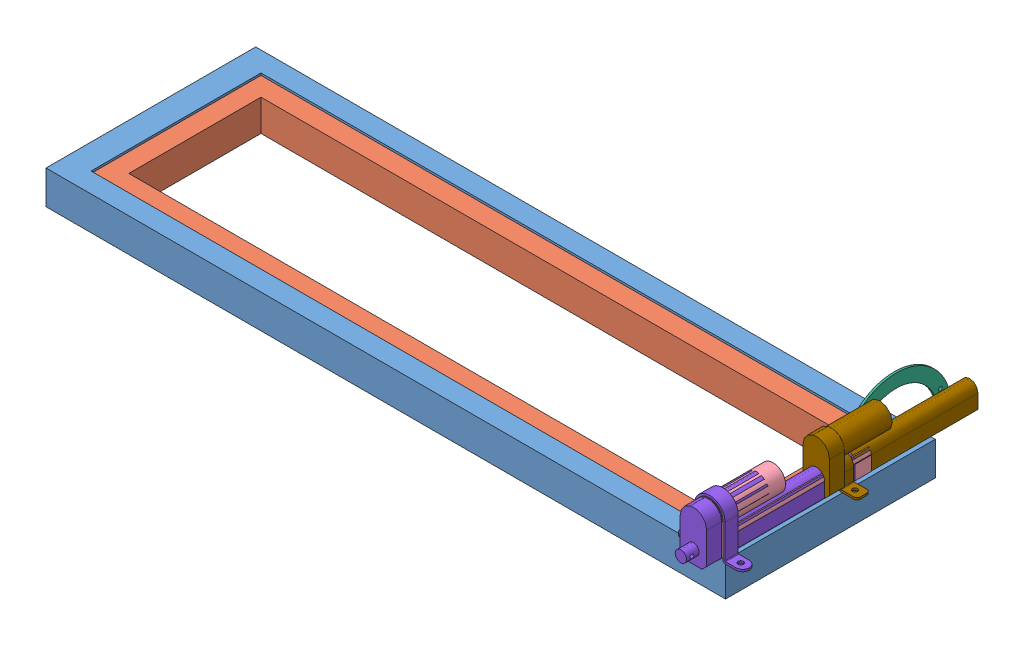
SolidWorks assembly Ensamblaje3, configuration Predeterminado. Lengths in mm.
Overall size (1059.65 147.79 411.91).
12 component instances, 9 part files, 23 mates.
Components (placement in the parent):
- Marco-1: Marco [Predeterminado] at (-53.8261 1.3636 0) size (1028.7 50.8 317.5)
- Ventana-1: Ventana [Predeterminado] at (-53.8261 1.3636 0) x (-1 0 0) z (0 0 -1) size (976.25 47.62 280.92)
- Bisabra-1: Bisabra [Default] at (97.2328 -11.1577 -174.3841) x (0 1 0) z (1 0 0) size (54 16 72) (flexible)
  - Bisagra-1: Bisagra [Default] at (4.5212 31.9216 19.0662) size (54 16 36)
  - Bisagra-2: Bisagra [Default] at (4.5212 31.9216 91.0662) x (1 0 0) z (0 0 -1) size (54 16 36)
- Motor150-1: Motor150 [Default] at (344.8659 -52.5107 -126.6133) size (40.01 75 401.08) (flexible)
  - motor150-1: motor150 [Predeterminado] at (96.608 131.4242 267.3633) x (1 0 0) z (0 -1 0) size (40.01 251 75)
  - eje150-1: eje150 [Predeterminado] at (96.608 124.1742 -70.716) x (-1 0 0) z (0 1 0) size (20 171 20)
- SoporteAperturaOpcion3-1: SoporteAperturaOpcion3 [Default] at (417.4739 75.5831 -75.6768) x (0 -0.100235 -0.994964) z (1 0 0) size (158.53 73.48 17.18)
- soportemotor18-2: soportemotor18 [Default] at (420.6489 78.9886 -85.0125) x (-1 0 0) z (0 0 1) size (25 30 20)
- SujetadorMotor-1: SujetadorMotor [Default] at (440.1188 79.4136 143.75) x (1 0 0) z (0 -1 0) size (103.17 251 78.17)
- SujetadorMotorDelantero-1: SujetadorMotorDelantero [Default] at (461.9608 78.2879 -38.25) x (1 0 0) z (0 -1 0) size (60.97 251 75)
Mates (geometry in assembly coordinates):
- Width1: width anti-aligned: plane of Marco-1 through (-545.9511 48.9886 0) normal (1 0 0); plane of Ventana-1 through (438.2989 48.9886 0) normal (-1 0 0); plane of Marco-1 through (-541.9511 48.9886 0) normal (-1 0 0); plane of Ventana-1 through (434.2989 48.9886 0) normal (1 0 0)
- Coincident2: coincident anti-aligned: plane of Marco-1 through (-53.8261 48.9886 -144.4625) normal (0 0 1); plane of Bisabra-1/Bisagra-2 through (152.2989 39.3636 -144.4625) normal (0 0 -1)
- Coincident3: coincident anti-aligned: plane of Marco-1 through (-53.8261 1.3636 0) normal (0 -1 0); plane of Bisabra-1/Bisagra-2 through (152.2989 1.3636 -144.4625) normal (0 1 0)
- Coincident4: coincident anti-aligned: plane of Ventana-1 through (-53.8261 48.9886 -140.4625) normal (0 0 -1); plane of Bisabra-1/Bisagra-1 through (152.2989 39.3636 -140.4625) normal (0 0 1)
- Coincident5: coincident anti-aligned: plane of Ventana-1 through (-53.8261 1.3636 0) normal (0 -1 0); plane of Bisabra-1/Bisagra-1 through (152.2989 1.3636 -140.4625) normal (0 1 0)
- Distance1: distance = 250 mm anti-aligned: plane of Marco-1 through (438.2989 48.9886 0) normal (-1 0 0); plane of Bisabra-1/Bisagra-2 through (188.2989 37.3636 -144.4625) normal (1 0 0)
- Concentric11: concentric anti-aligned: cylinder of Motor150-1/eje150-1 through (453.9739 71.6636 -209.3292) axis (-1 0 0) radius 3; cylinder of SoporteAperturaOpcion3-1 through (414.2989 71.6636 -209.3292) axis (1 0 0) radius 3
- Tangent1: tangent anti-aligned: cylinder of Motor150-1/eje150-1 through (441.4739 71.6636 -218.3292) axis (0 0 1) radius 10; plane of SoporteAperturaOpcion3-1 through (431.4739 75.5831 -75.6768) normal (1 0 0)
- Parallel7: parallel anti-aligned: plane of Marco-1 through (-53.8261 52.1636 0) normal (0 1 0); plane of Motor150-1/motor150-1 through (441.4739 52.1636 -68.25) normal (0 -1 0)
- Coincident43: coincident anti-aligned: plane of Ventana-1 through (-53.8261 48.9886 0) normal (0 1 0); plane of soportemotor18-2 through (420.6489 48.9886 -65.0125) normal (0 -1 0)
- Coincident48: coincident anti-aligned: plane of Ventana-1 through (-53.8261 48.9886 0) normal (0 1 0); plane of soportemotor18-2 through (420.6489 48.9886 -65.0125) normal (0 -1 0)
- Distance24: distance = 15 mm anti-aligned: plane of soportemotor18-2 through (416.4739 53.1636 -85.0125) normal (0 0 -1); plane of Ventana-1 through (-53.8261 48.9886 -100.0125) normal (0 0 1)
- Concentric15: concentric aligned: cylinder of SoporteAperturaOpcion3-1 through (414.2989 68.9886 -75.0125) axis (1 0 0) radius 3; cylinder of soportemotor18-2 through (395.6489 68.9886 -75.0125) axis (1 0 0) radius 3
- Coincident50: coincident anti-aligned: plane of SoporteAperturaOpcion3-1 through (417.4739 43.0511 -142.7141) normal (1 0 0); plane of soportemotor18-2 through (417.4739 78.9886 -65.0125) normal (-1 0 0)
- Coincident51: coincident anti-aligned: plane of Marco-1 through (-53.8261 52.1636 0) normal (0 1 0); plane of Motor150-1/motor150-1 through (441.4739 52.1636 -68.25) normal (0 -1 0)
- Width2: width anti-aligned: plane of Motor150-1/motor150-1 through (421.4739 51.6636 163.75) normal (-1 0 0); plane of Motor150-1/motor150-1 through (461.4739 51.6636 163.75) normal (1 0 0); plane of Marco-1 through (460.5239 52.1636 0) normal (1 0 0); plane of Marco-1 through (422.4239 1.3636 -128.5875) normal (-1 0 0)
- Distance25: distance = 5 mm aligned: plane of Marco-1 through (-53.8261 52.1636 158.75) normal (0 0 1); plane of Motor150-1/motor150-1 through (441.4739 106.6575 163.75) normal (0 0 1)
- Width3: width aligned: plane of SujetadorMotor-1 through (464.6489 59.1636 163.75) normal (1 0 0); plane of SujetadorMotor-1 through (418.2989 59.1636 163.75) normal (-1 0 0); plane of Motor150-1/motor150-1 through (461.4739 51.6636 163.75) normal (1 0 0); plane of Motor150-1/motor150-1 through (421.4739 51.6636 163.75) normal (-1 0 0)
- Coincident52: coincident aligned: plane of Motor150-1/motor150-1 through (441.4739 106.6575 163.75) normal (0 0 1); plane of SujetadorMotor-1 through (417.2989 52.1636 163.75) normal (0 0 1)
- Coincident54: coincident anti-aligned: plane of Marco-1 through (-53.8261 52.1636 0) normal (0 1 0); plane of SujetadorMotor-1 through (388.2989 52.1636 163.75) normal (0 -1 0)
- Coincident55: coincident aligned: plane of SujetadorMotor-1 through (464.6489 52.1636 163.75) normal (0 -1 0); plane of SujetadorMotorDelantero-1 through (457.4418 52.1636 -18.25) normal (0 -1 0)
- Coincident56: coincident anti-aligned: plane of Motor150-1/motor150-1 through (454.2668 78.9136 -68.25) normal (1 0 0); plane of SujetadorMotorDelantero-1 through (454.2668 55.3386 -18.25) normal (-1 0 0)
- Distance26: distance = 30 mm aligned: plane of SujetadorMotorDelantero-1 through (458.4418 52.1636 -38.25) normal (0 0 -1); plane of Motor150-1/motor150-1 through (441.4739 78.9136 -68.25) normal (0 0 -1)
